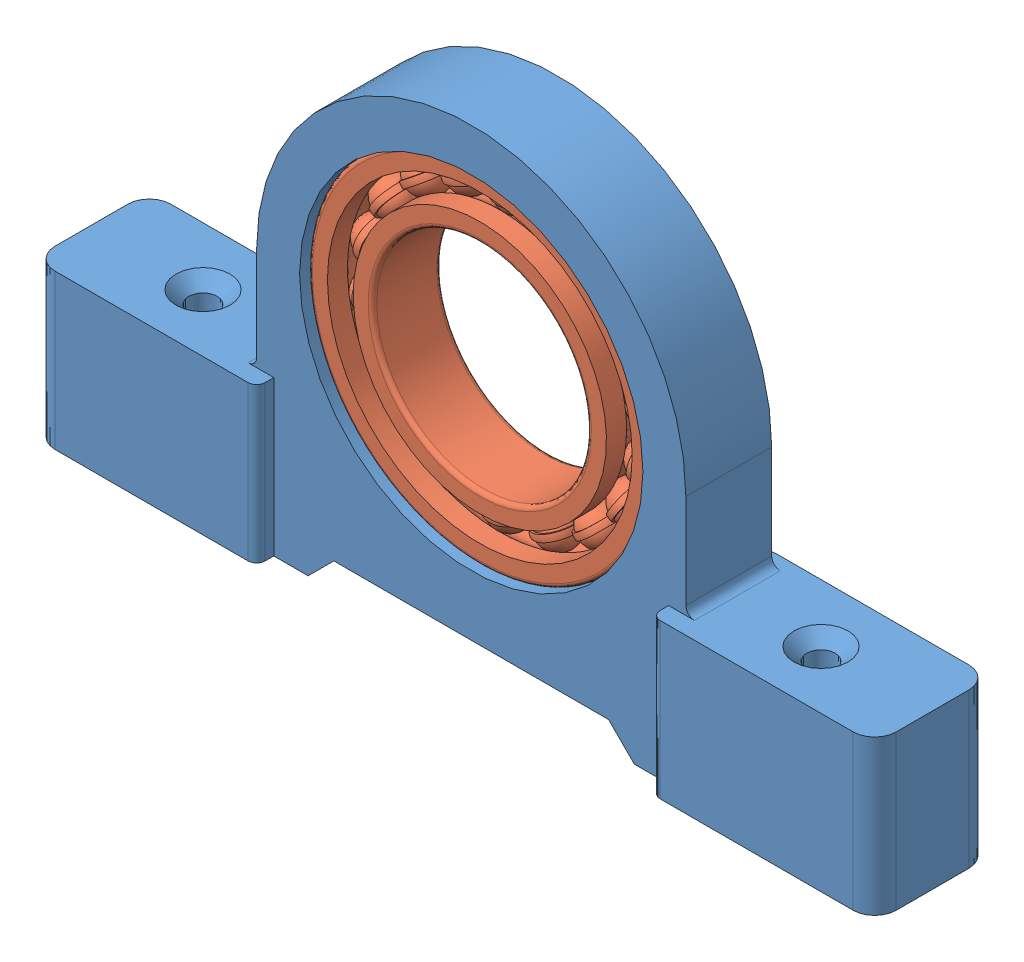
SolidWorks assembly bearing block, configuration Default. Lengths in mm.
Overall size (196 111.9 27).
2 component instances, 2 part files, 2 mates.
Components (placement in the parent):
- housing-1: housing [Default] at (66.9883 111.593 150.2765) size (196 110 27)
- radial ball bearing_68_skf-1: radial ball bearing_68_skf [SKF - 6010 - 18,DE,AC,18_68] at (66.9883 111.593 150.2765) x (0 0 1) z (-0.930014 0.367525 0) size (16 80 80)
Mates (geometry in assembly coordinates):
- Concentric1: concentric anti-aligned: cylinder of housing-1 through (66.9883 111.593 160.2765) axis (0 0 -1) radius 40; cylinder of bearing 6010-1 through (66.9883 111.593 129.639) axis (0 0 1) radius 40
- Width1: width anti-aligned: plane of bearing 6010-1 through (77.8303 139.0284 142.2765) normal (0 0 -1); plane of housing-1 through (76.5439 135.7733 158.2765) normal (0 0 1); plane of bearing 6010-1 through (66.9883 111.593 160.2765) normal (0 0 1); plane of housing-1 through (66.9883 111.593 140.2765) normal (0 0 -1)
